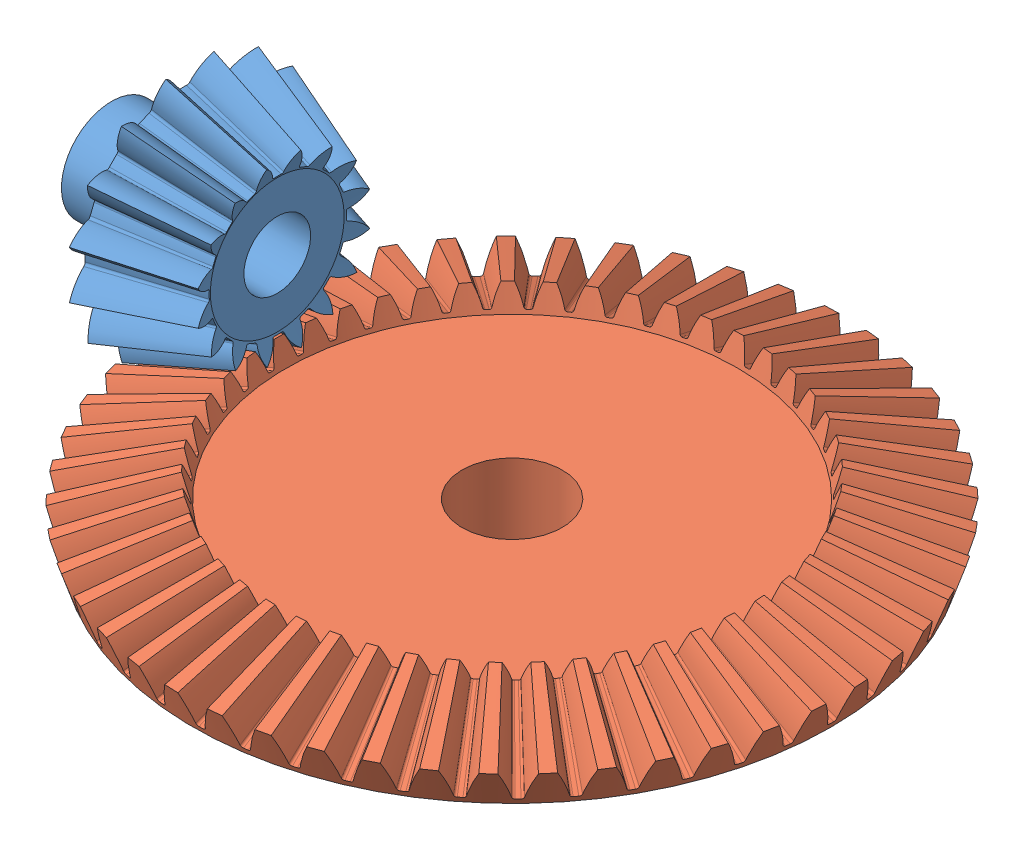
SolidWorks assembly Bevel Gear with Animation, configuration Default. Lengths in mm.
Overall size (331.44 136.44 331.37).
2 component instances, 2 part files, 6 mates.
Components (placement in the parent):
- straight bevel pinion_ai-1: straight bevel pinion_ai [Inch - Straight bevel pinion 5DP16PT 49GT 20PA 1.5FW ---16O1.5H6MD1.0N] at (-126.0113 50.3522 0) x (1 0 0) z (0 -0.378833 -0.925465) size (67.78 92.37 92.37)
- straight bevel gear_ai-1: straight bevel gear_ai [Inch - Straight bevel gear 5DP 49GT 16PT 20PA 1.5FW ---49O3.0H3.0MD1.5N] x (0 1 0) z (-0.913289 0 -0.407311) size (50.43 250.89 251.02)
Mates (geometry in assembly coordinates):
- Coincident1: coincident anti-aligned: plane of straight bevel gear_ai-1 through (0 0 0) normal (0 -1 0); plane of assembly through (0 0 0) normal (0 1 0)
- Concentric1: concentric: cylinder of ? through (0 76.2001 0) axis (0 -1 0) radius 19.05
- Coincident2: coincident: point of straight bevel pinion_ai-1; point of straight bevel gear_ai-1
- Coincident3: coincident: axis of straight bevel pinion_ai-1 through (-89.3418 50.3522 0) axis (-1 0 0); plane of assembly
- Perpendicular1: perpendicular: axis of straight bevel pinion_ai-1 through (-89.3418 50.3522 0) axis (-1 0 0); axis of straight bevel gear_ai-1 through (0 12.5567 0) axis (0 1 0)
- GearMate1: gear = 1244.6 : 406.4 mm: cylinder of straight bevel pinion_ai-1 through (26.3887 50.3522 0) axis (-1 0 0) radius 12.7; cylinder of straight bevel gear_ai-1 through (0 76.2001 0) axis (0 -1 0) radius 19.05
